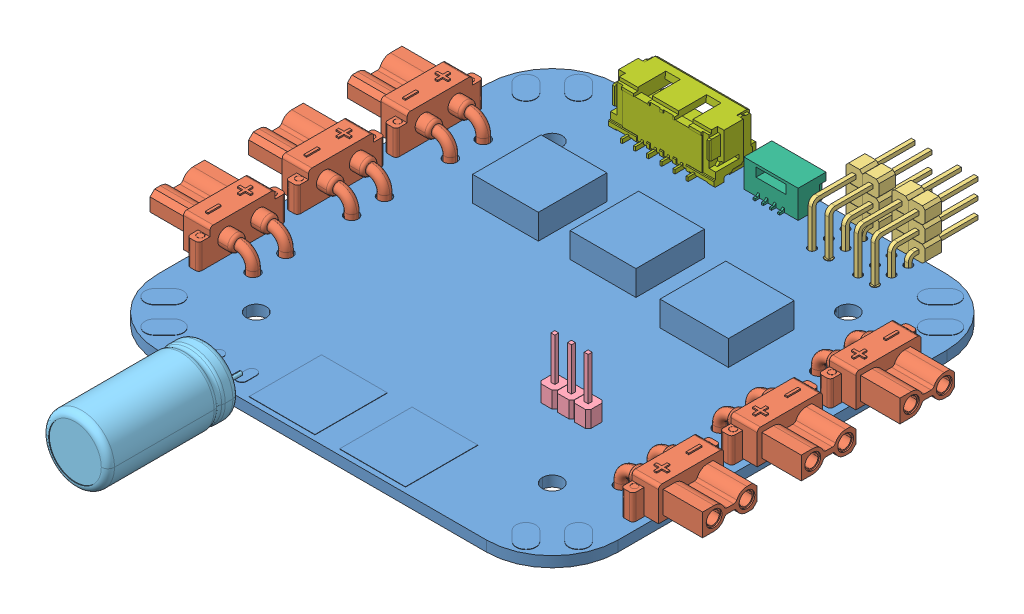
SolidWorks assembly pm03d-full_asm.stp, configuration Default. Lengths in mm.
Overall size (84.2 13.5 98.76).
13 component instances, 7 part files, 0 mates.
Components (placement in the parent):
- PCB-PM03D.stp-1: PCB-PM03D.stp [Default] at origin size (70 5.4 70)
- XT30PW-F.stp-1: XT30PW-F.stp [Default] at (-31.1 4.25 15) x (0 0 -1) z (0 1 0) size (13.3 14.9 7.2)
- XT30PW-F.stp-2: XT30PW-F.stp [Default] at (-31.1 4.25 0) x (0 0 -1) z (0 1 0) size (13.3 14.9 7.2)
- XT30PW-F.stp-3: XT30PW-F.stp [Default] at (-31.1 4.25 -15) x (0 0 -1) z (0 1 0) size (13.3 14.9 7.2)
- XT30PW-F.stp-4: XT30PW-F.stp [Default] at (31.1 4.25 15) x (0 0 1) z (0 1 0) size (13.3 14.9 7.2)
- XT30PW-F.stp-5: XT30PW-F.stp [Default] at (31.1 4.25 0) x (0 0 1) z (0 1 0) size (13.3 14.9 7.2)
- XT30PW-F.stp-6: XT30PW-F.stp [Default] at (31.1 4.25 -15) x (0 0 1) z (0 1 0) size (13.3 14.9 7.2)
- eBom-prt2.stp-1: eBom-prt2.stp [Default] at (17.67 6.7 -34.56) x (1 0 0) z (0 1 0) size (5.04 15.93 10.03)
- eBom-prt2.stp-2: eBom-prt2.stp [Default] at (24.67 6.7 -34.56) x (1 0 0) z (0 1 0) size (5.04 15.93 10.03)
- eBom-prt3.stp-1: eBom-prt3.stp [Default] at (18.25 1.6 11.54) size (7.58 11.5 2.5)
- DIANRONG-1000-ZHI.stp-1: DIANRONG-1000-ZHI.stp [Default] at (-17.36 2.1 35.2) x (-1 0 0) z (0 1 0) size (10 23 10)
- BM04B-WO.stp-1: BM04B-WO.stp [Default] at (2.5 3.725 -30.75) x (-1 0 0) z (0 -1 0) size (8.25 4.95 4.25)
- 5024940670.stp-1: 5024940670.stp [Default] at (-12 5.2 -34.575) size (16 6.9 8.5)
